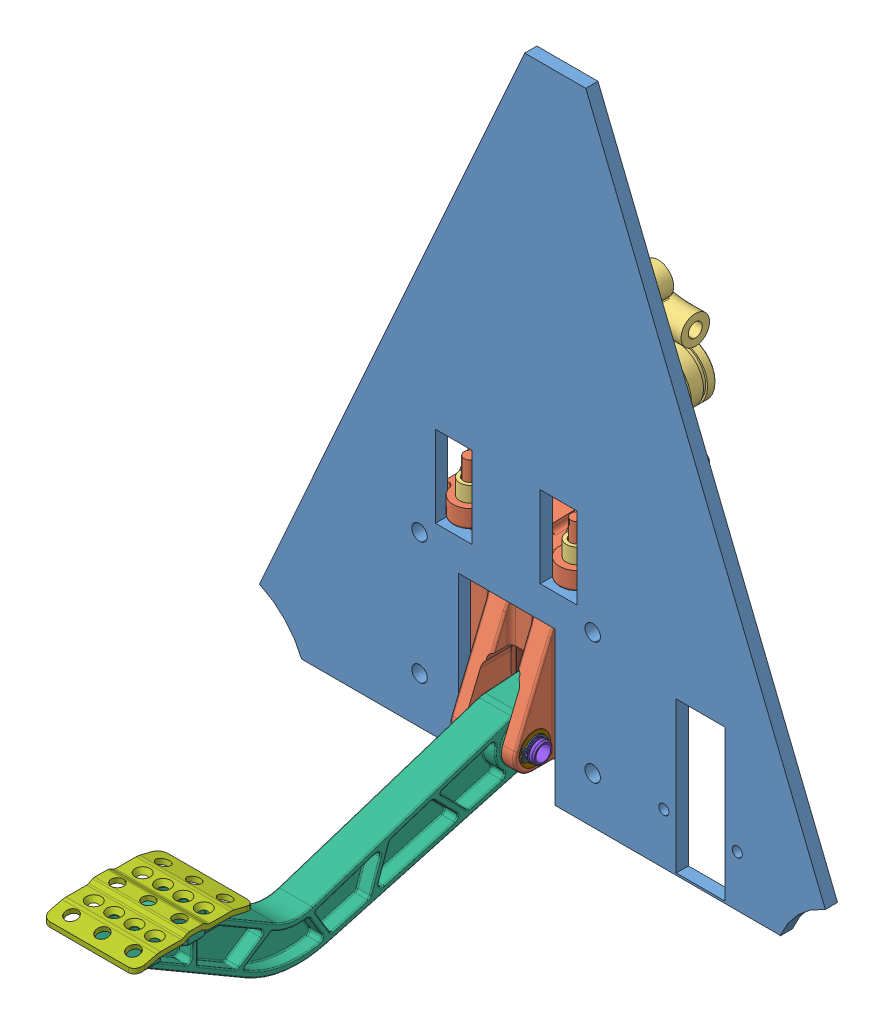
SolidWorks assembly BR22-1300-BASM, configuration Default. Lengths in mm.
Overall size (352.85 422.61 340.72).
24 component instances, 13 part files, 3 mates.
Components (placement in the parent):
- BR22-1104-PRT-1: BR22-1104-PRT [Default] at (581.6839 -180.7586 -232.53) size (352.85 397.07 7.62)
- BrakesAssem2-1: BrakesAssem2 [Default] at (533.9206 -504.1753 -497.9877) x (-1 0 0) z (0 1 0) size (133.35 340.72 297.58)
  - newBrakeMS_assem-1: newBrakeMS_assem [Default] at (94.891 166.2323 176.071) size (133.35 95.19 257.05)
    - pedalmount-1: pedalmount [Default] at (-8.0254 86.5254 126.5371) size (133.35 93.62 137.28)
    - mastercylinder asm-1: mastercylinder asm [Default] at (25.2486 67.4754 134.5381) x (1 0 0) z (0 0 -1) size (45.21 75.99 223.71)
      - mastercylinder-1: mastercylinder [Default] at origin size (45.21 75.99 154.88)
      - mastercylinder retaining washer-1: mastercylinder retaining washer [Default] at (0 0 17.145) size (20.83 20.83 1.91)
      - mastercylinder pushrod-1: mastercylinder pushrod [Default] at (0 0 90.551) x (-0.12806 0.991766 0) z (0 0 1) size (10.67 10.67 107.24)
    - mastercylinder asm-2: mastercylinder asm [Default] at (91.7966 67.4754 134.5381) x (1 0 0) z (0 0 -1) size (45.21 75.99 223.71)
      - mastercylinder-1: mastercylinder [Default] at origin size (45.21 75.99 154.88)
      - mastercylinder retaining washer-1: mastercylinder retaining washer [Default] at (0 0 17.145) size (20.83 20.83 1.91)
      - mastercylinder pushrod-1: mastercylinder pushrod [Default] at (0 0 90.551) x (-0.12806 0.991766 0) z (0 0 1) size (10.67 10.67 107.24)
  - brake_pedal-1: brake_pedal [Default] at (152.8421 275.6176 198.9761) x (-1 0 0) z (0 -0.003692 0.999993) size (37.97 301.81 72.18)
  - brake_pedal_pad-1: brake_pedal_pad [Default] at (182.5601 496.5881 214.4052) x (0 -0.999993 -0.003692) z (-1 0 0) size (73.98 8.25 58.98)
  - bushing-1: bushing [Default] at (152.6707 275.6176 198.9761) x (0 0.840128 -0.542388) z (1 0 0) size (12.65 12.65 49.7)
  - bushing washer-1: bushing washer [Default] at (174.0892 275.6176 198.9761) x (0 1 0) z (0 0 1) size (19.1 0.36 19.1)
  - bushing washer-3: bushing washer [Default] at (133.3476 275.6176 198.9761) x (0 1 0) z (0 0 1) size (19.1 0.36 19.1)
  - retainingring-1: retainingring [Default] at (174.0892 275.6176 198.9761) x (0 0 -1) z (1 0 0) size (14.22 15.93 0.89)
  - retainingring-2: retainingring [Default] at (132.992 275.6176 198.9761) x (0 0 1) z (-1 0 0) size (14.22 15.93 0.89)
  - clevis2022-1: clevis2022 [Default] at (120.3301 222.5316 199.4968) x (-1 0 0) z (0 0 -1) size (21.97 22.28 44.25)
  - clevis2022-2: clevis2022 [Default] at (186.4971 244.8836 199.4968) x (1 0 0) z (0 0 -1) size (21.97 22.28 44.25)
  - clevis pin2022-1: clevis pin2022 [Default] at (120.3301 221.8966 199.4968) x (0 0 1) z (-1 0 0) size (14.27 23.6 14.27)
  - Balance bar2022-1: Balance bar2022 [Default] at (155.1762 233.9997 199.256) x (0 0.874504 0.485018) z (0 -0.485018 0.874504) size (20.15 121.21 20.15)
  - clevis pin2022-2: clevis pin2022 [Default] at (186.4971 221.9728 199.4968) x (0 0 -1) z (1 0 0) size (14.27 23.6 14.27)
Mates (geometry in assembly coordinates):
- Concentric9: concentric anti-aligned: circle of BR22-1104-PRT-1; circle of BrakesAssem2-1/newBrakeMS_assem-1/pedalmount-1
- Coincident5: coincident anti-aligned: plane of BR22-1104-PRT-1 through (581.6839 -180.7586 -232.53) normal (0 0 -1); plane of BrakesAssem2-1/newBrakeMS_assem-1/pedalmount-1 through (313.705 -248.9642 -232.53) normal (0 0 1)
- Concentric13: concentric anti-aligned: circle of BR22-1104-PRT-1; circle of BrakesAssem2-1/newBrakeMS_assem-1/pedalmount-1
